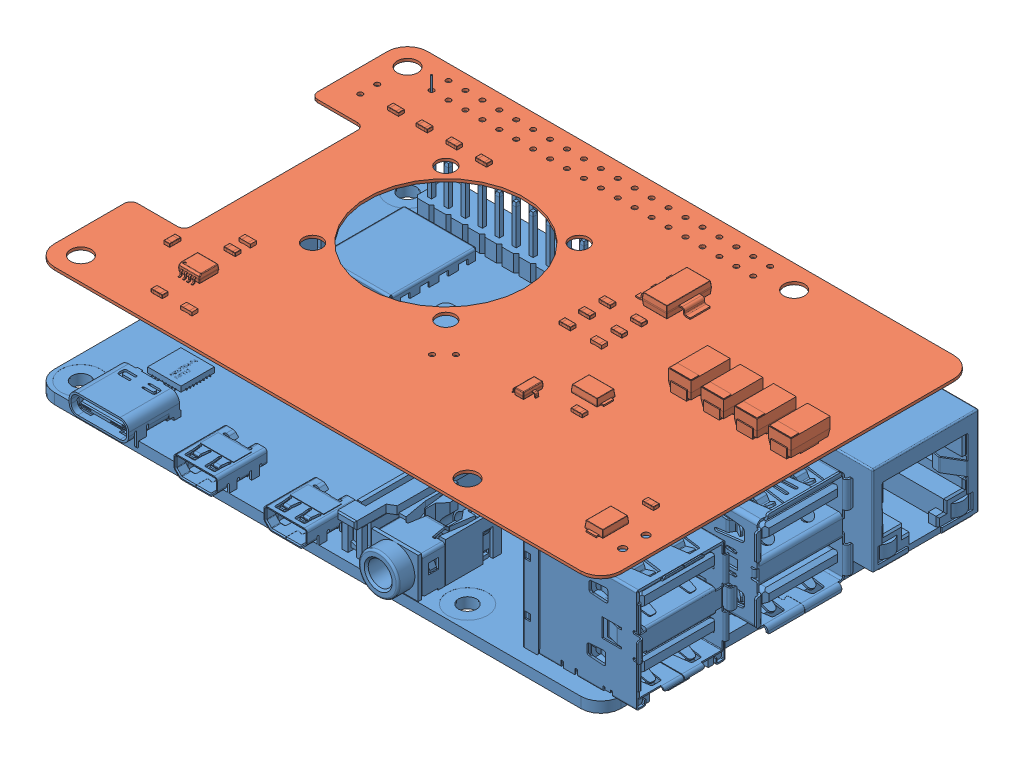
SolidWorks assembly Assem1, configuration Default. Lengths in mm.
Overall size (88.99 22.84 58.4).
2 component instances, 2 part files, 6 mates.
Components (placement in the parent):
- Raspberry Pi 4 Model B-1: Raspberry Pi 4 Model B [Default] at (28.1691 38.5384 69.2999) size (88.99 22 58.4)
- PCB1-1: PCB1 [Default] at (-10.8309 55.6305 93.7999) x (1 0 0) z (0 1 0) size (85 56 3.26)
Mates (geometry in assembly coordinates):
- Concentric2: concentric: cylinder of Raspberry Pi 4 Model B-1 through (47.1691 39.3384 44.7999) axis (0 1 0) radius 1.35; cylinder of ? through (47.1691 59.4693 44.7999) axis (0 -1 0) radius 1.5
- Concentric3: concentric: cylinder of Raspberry Pi 4 Model B-1 through (-10.8309 39.3384 44.7999) axis (0 1 0) radius 1.35; cylinder of ? through (-10.8309 59.4693 44.7999) axis (0 -1 0) radius 1.5
- Concentric4: concentric: cylinder of Raspberry Pi 4 Model B-1 through (-10.8309 39.3384 44.7999) axis (0 1 0) radius 1.35; cylinder of ? through (-10.8309 44.414 44.7999) axis (0 -1 0) radius 1.5
- Concentric5: concentric: cylinder of Raspberry Pi 4 Model B-1 through (47.1691 39.3384 44.7999) axis (0 1 0) radius 1.35; cylinder of ? through (47.1691 44.414 44.7999) axis (0 -1 0) radius 1.5
- Concentric9: concentric: cylinder of Raspberry Pi 4 Model B-1 through (-10.8309 39.3384 93.7999) axis (0 1 0) radius 1.35; circle of PCB1-1
- Concentric10: concentric: cylinder of Raspberry Pi 4 Model B-1 through (47.1691 39.3384 44.7999) axis (0 1 0) radius 1.35; cylinder of PCB1-1 through (47.1691 55.219 44.7999) axis (0 -1 0) radius 1.55
